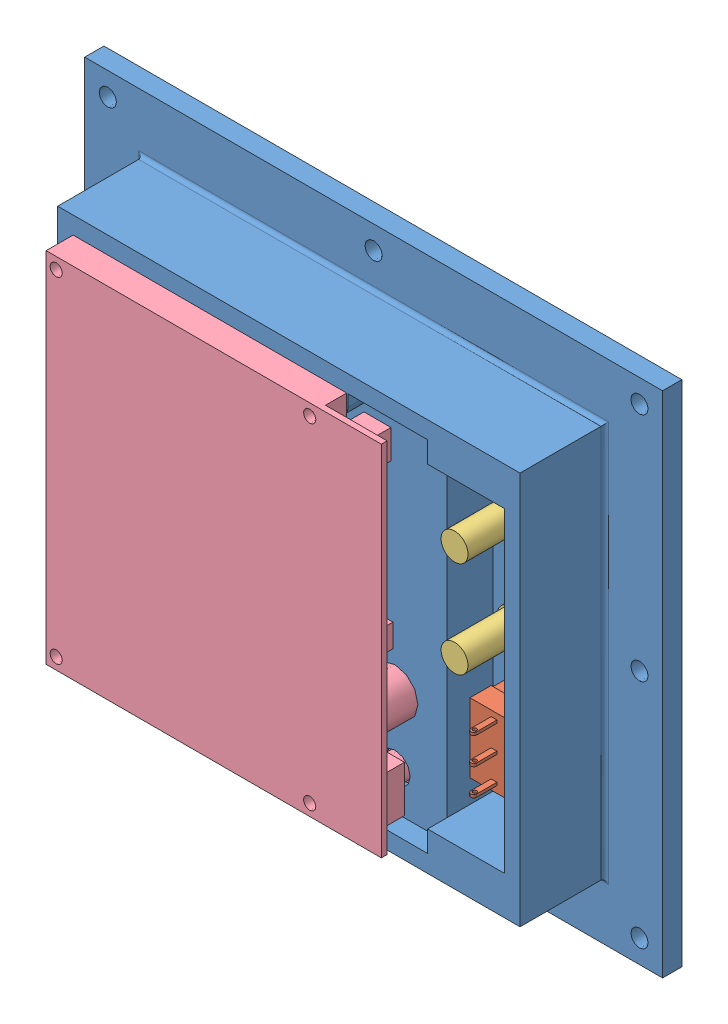
SolidWorks assembly Дисплей с креплением, configuration По умолчанию. Lengths in mm.
Overall size (150 132 34).
5 component instances, 4 part files, 16 mates.
Components (placement in the parent):
- Крепление дисплея-1: Крепление дисплея [По умолчанию] at origin size (150 132 27)
- Тумблер-1: Тумблер [По умолчанию] at (100 38 13) x (0 -1 0) z (1 0 0) size (20.87 23.5 14.5)
- Светодиод-1: Светодиод [По умолчанию] at (106 80 -2) x (0 0 1) z (0 1 0) size (27 10 10)
- Светодиод-2: Светодиод [По умолчанию] at (106 55 -2) x (0 0 1) z (-1 0 0) size (27 10 10)
- Дисплей ГМ-2: Дисплей ГМ [По умолчанию] at (91 97.5 29) x (0 -1 0) z (1 0 0) size (93 31 87)
Mates (geometry in assembly coordinates):
- Совпадение1: coincident aligned: plane of Крепление дисплея-1 through (0 0 0) normal (0 0 1); plane of assembly through (0 0 0) normal (0 0 1)
- Совпадение2: coincident aligned: plane of Крепление дисплея-1 through (0 0 0) normal (0 1 0); plane of assembly through (0 0 0) normal (0 1 0)
- Совпадение3: coincident aligned: plane of Крепление дисплея-1 through (0 0 0) normal (1 0 0); plane of assembly through (0 0 0) normal (1 0 0)
- Совпадение9: coincident anti-aligned: plane of Крепление дисплея-1 through (0 0 2) normal (0 0 -1); plane of Тумблер-1 through (100 38 2) normal (0 0 1)
- Совпадение10: coincident anti-aligned: plane of Крепление дисплея-1 through (99.5 38.5 -5) normal (1 0 0); plane of Тумблер-1 through (99.5 21.75 5.5) normal (-1 0 0)
- Совпадение11: coincident anti-aligned: plane of Крепление дисплея-1 through (99.5 20 -5) normal (0 1 0); plane of Тумблер-1 through (112.5 20 13) normal (0 -1 0)
- Концентричный1: concentric anti-aligned: cylinder of Крепление дисплея-1 through (106 80 22) axis (0 0 -1) radius 4; cylinder of Светодиод-1 through (106 80 25) axis (0 0 1) radius 4
- Совпадение12: coincident anti-aligned: plane of Крепление дисплея-1 through (0 0 2) normal (0 0 -1); circle of Светодиод-1
- Параллельность1: parallel aligned: plane of Светодиод-1 through (106 80 -2) normal (0 1 0); plane of assembly through (0 0 0) normal (0 1 0)
- Концентричный2: concentric anti-aligned: cylinder of Крепление дисплея-1 through (106 55 22) axis (0 0 -1) radius 4; cylinder of Светодиод-2 through (106 55 25) axis (0 0 1) radius 4
- Совпадение13: coincident anti-aligned: plane of Крепление дисплея-1 through (0 0 2) normal (0 0 -1); plane of Светодиод-2 through (106 60 2) normal (0 0 1)
- Параллельность2: parallel aligned: plane of Крепление дисплея-1 through (116 98 0) normal (-1 0 0); plane of Светодиод-2 through (106 55 -2) normal (-1 0 0)
- Параллельность3: parallel aligned: plane of Крепление дисплея-1 through (4 98 0) normal (1 0 0); plane of assembly through (0 0 0) normal (1 0 0)
- Concentric1: concentric anti-aligned: cylinder of Крепление дисплея-1 through (6.6 94.5 22) axis (0 0 -1) radius 1.2; cylinder of Дисплей ГМ-2 through (6.6 94.5 22) axis (0 0 1) radius 1.6
- Concentric2: concentric anti-aligned: cylinder of Крепление дисплея-1 through (72.4 7.5 22) axis (0 0 -1) radius 1.2; cylinder of Дисплей ГМ-2 through (72.4 7.5 22) axis (0 0 1) radius 1.6
- Coincident2: coincident anti-aligned: plane of Крепление дисплея-1 through (0 0 22) normal (0 0 1); plane of Дисплей ГМ-2 through (91 97.5 22) normal (0 0 -1)
